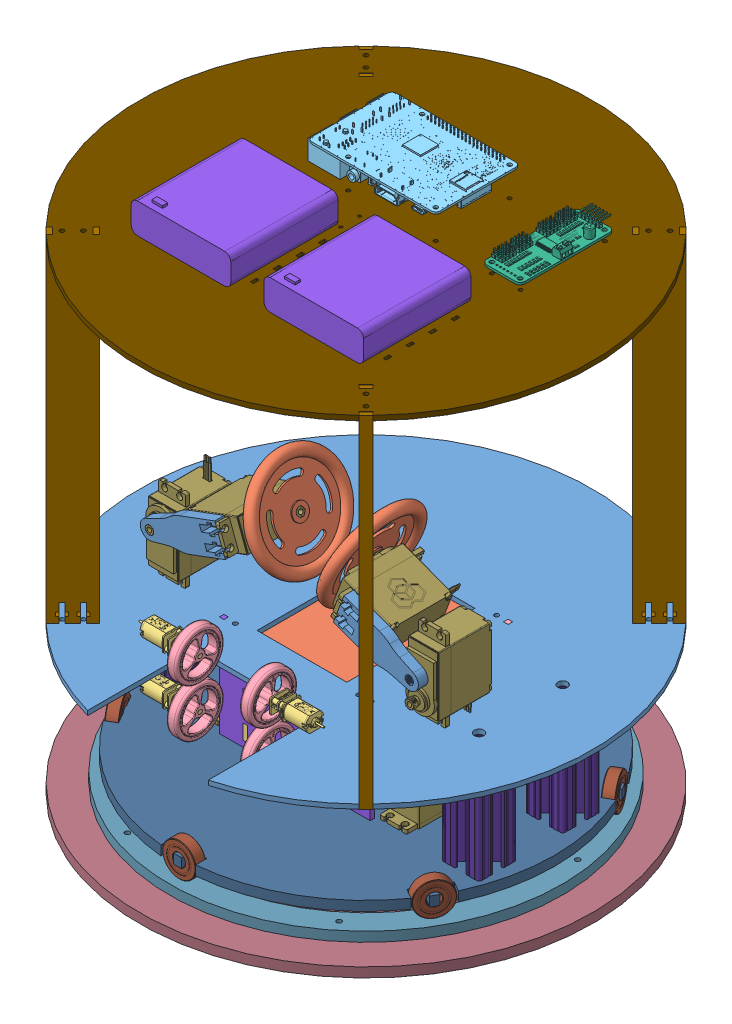
SolidWorks assembly Big_assembly, configuration Default. Lengths in mm.
Overall size (883.19 344.85 416.68).
60 component instances, 26 part files, 69 mates.
Components (placement in the parent):
- Top_Plate-1: Top_Plate [Default] at (43.1232 135.9669 213.6258) size (300 3 294.57)
- Deck-1: Deck [Default] at (43.1232 119.9669 213.6258) size (883.19 16 224.45)
- wall_long_side-1: wall_long_side [Default] at (11.6232 103.9669 213.6258) x (0 0 1) z (-1 0 0) size (94.4 64 3)
- wall_long_side-2: wall_long_side [Default] at (77.6232 103.9669 213.6258) x (0 0 1) z (-1 0 0) size (94.4 64 3)
- wall_back-1: wall_back [Default] at (43.1232 103.9669 166.4258) x (0 0 1) z (-1 0 0) size (3 67 100)
- box_bottom-1: box_bottom [Default] at (43.1232 81.8367 213.6258) size (87.5 3 88)
- Spring-1: Spring [Default] at (81.3732 96.1631 233.6258) size (7.89 47.53 7.89)
- 92125A130_TYPE 18-8 SS FLAT-HEAD SOCKET CAP SCREW-1: 92125A130_TYPE 18-8 SS FLAT-HEAD SOCKET CAP SCREW [92125A130] at (74.6232 132.4669 233.6258) x (0 -0.041478 -0.999139) z (-1 0 0) size (6 6 10.3)
- Spring-2: Spring [Default] at (4.3732 96.1631 233.6258) size (7.89 47.53 7.89)
- Spring-3: Spring [Default] at (81.3732 96.1631 193.6258) size (7.89 47.53 7.89)
- Spring-4: Spring [Default] at (4.3732 96.1631 193.6258) size (7.89 47.53 7.89)
- 92125A130_TYPE 18-8 SS FLAT-HEAD SOCKET CAP SCREW-2: 92125A130_TYPE 18-8 SS FLAT-HEAD SOCKET CAP SCREW [92125A130] at (74.6232 132.4669 193.6258) x (0 -0.041478 -0.999139) z (-1 0 0) size (6 6 10.3)
- 92125A130_TYPE 18-8 SS FLAT-HEAD SOCKET CAP SCREW-3: 92125A130_TYPE 18-8 SS FLAT-HEAD SOCKET CAP SCREW [92125A130] at (11.6232 132.4669 233.6258) x (0 0.041478 0.999139) z (1 0 0) size (6 6 10.3)
- 92125A130_TYPE 18-8 SS FLAT-HEAD SOCKET CAP SCREW-4: 92125A130_TYPE 18-8 SS FLAT-HEAD SOCKET CAP SCREW [92125A130] at (11.6232 132.4669 193.6258) x (0 0.041478 0.999139) z (1 0 0) size (6 6 10.3)
- wall_front_v02-1: wall_front_v02 [Default] at (43.1232 103.9669 260.8258) x (0 0 -1) z (1 0 0) size (3 67 100)
- 220_x_40mm_vertical_beam_1-4_in_t-slots-1: 220_x_40mm_vertical_beam_1-4_in_t-slots [Default] at (129.2665 138.9669 122.9924) x (0.707107 0 -0.707107) z (0 -1 0) size (25 6.35 226)
- assem3-1: assem3 [Default] at (169.2489 77.438 270.0894) x (0.934159 0 0.356856) z (-0.356856 0 0.934159) size (322.75 56.87 322.75)
  - lazy_susan_protoype-1: lazy_susan_protoype [Default] at (-137.9709 -17.8212 -7.7373) x (0.356856 0 0.934159) z (-0.934159 0 0.356856) size (250 6.35 250)
  - 5972K501_BALL BEARING-1: 5972K501_BALL BEARING [5972K501] at (-61.9864 -14.6462 -101.2605) x (-0.500804 -0.763962 -0.406887) z (-0.630577 0 0.776126) size (22 22 7)
  - servo-1: servo [Default] at (-83.0236 -8.9712 -18.0228) x (-0.934159 0 0.356856) z (0.356856 0 0.934159) size (20 45.1 60)
  - servo-2: servo [Default] at (-185.7811 -8.9712 21.2314) x (-0.934159 0 0.356856) z (0.356856 0 0.934159) size (20 45.1 60)
  - 5972K501_BALL BEARING-5: 5972K501_BALL BEARING [5972K501] at (-18.9852 -14.6462 11.3057) x (0.101972 -0.763962 -0.637152) z (-0.987434 0 -0.158033) size (22 22 7)
  - 5972K501_BALL BEARING-6: 5972K501_BALL BEARING [5972K501] at (-94.9697 -14.6462 104.8289) x (0.602776 -0.763962 -0.230265) z (-0.356856 0 -0.934159) size (22 22 7)
  - 5972K501_BALL BEARING-7: 5972K501_BALL BEARING [5972K501] at (-213.9555 -14.6462 85.786) x (0.500804 -0.763962 0.406887) z (0.630577 0 -0.776126) size (22 22 7)
  - base-1: base [Default] at (-137.9709 -38.3462 -7.7373) size (300 6.35 300)
  - new_rail-1: new_rail [Default] at (-137.9709 -31.9962 -7.7373) size (260 6.35 260)
  - new_base_gear-1: new_base_gear [Default] at (-137.9709 -30.0764 -7.7373) x (0 0 -1) z (0 1 0) size (59.22 59.28 6.35)
  - new_servo_gear-1: new_servo_gear [Default] at (-189.3497 -28.8212 11.8898) x (0.783336 0 0.621598) z (0 1 0) size (59.22 59.28 6.35)
  - new_servo_gear-2: new_servo_gear [Default] at (-86.5922 -27.8212 -27.3644) x (0.136575 0 0.99063) z (0 1 0) size (59.22 59.28 6.35)
  - 5972K501_BALL BEARING-8: 5972K501_BALL BEARING [5972K501] at (-256.9567 -14.6462 -26.7802) x (-0.101972 -0.763962 0.637152) z (0.987434 0 0.158033) size (22 22 7)
  - 5972K501_BALL BEARING-9: 5972K501_BALL BEARING [5972K501] at (-180.9721 -14.6462 -120.3035) x (-0.602776 -0.763962 0.230265) z (0.356856 0 0.934159) size (22 22 7)
- 47065T411_ALUMINUM T-SLOTTED FRAMING EXTRUSION-1: 47065T411_ALUMINUM T-SLOTTED FRAMING EXTRUSION [47065T411] at (-59.5768 100.9669 185.9258) x (1 0 0) z (0 -1 0) size (25.4 25.4 70)
- 47065T411_ALUMINUM T-SLOTTED FRAMING EXTRUSION-4: 47065T411_ALUMINUM T-SLOTTED FRAMING EXTRUSION [47065T411] at (-59.5768 100.9669 241.3258) x (1 0 0) z (0 1 0) size (25.4 25.4 70)
- 47065T411_ALUMINUM T-SLOTTED FRAMING EXTRUSION-5: 47065T411_ALUMINUM T-SLOTTED FRAMING EXTRUSION [47065T411] at (145.8232 100.9669 241.3258) x (-1 0 0) z (0 -1 0) size (25.4 25.4 70)
- 47065T411_ALUMINUM T-SLOTTED FRAMING EXTRUSION-6: 47065T411_ALUMINUM T-SLOTTED FRAMING EXTRUSION [47065T411] at (145.8232 100.9669 185.9258) x (-1 0 0) z (0 1 0) size (25.4 25.4 70)
- 220_x_40mm_vertical_beam_1-4_in_t-slots-2: 220_x_40mm_vertical_beam_1-4_in_t-slots [Default] at (133.7566 138.9669 299.7691) x (0.707107 0 0.707107) z (0 -1 0) size (25 6.35 226)
- 220_x_40mm_vertical_beam_1-4_in_t-slots-3: 220_x_40mm_vertical_beam_1-4_in_t-slots [Default] at (-43.0201 138.9669 304.2592) x (-0.707107 0 0.707107) z (0 -1 0) size (25 6.35 226)
- 220_x_40mm_vertical_beam_1-4_in_t-slots-4: 220_x_40mm_vertical_beam_1-4_in_t-slots [Default] at (-47.5102 138.9669 127.4825) x (-0.707107 0 -0.707107) z (0 -1 0) size (25 6.35 226)
- electronics_mount_2-1: electronics_mount_2 [Default] at (-62.9428 358.9669 319.6918) size (300 3.17 300)
- servo-1: servo [Default] at (-43.0683 165.9669 253.4758) x (1 0 0) z (0 -1 0) size (20 45.1 60)
- servo_to_servo_horn-1: servo_to_servo_horn [Default] at (-43.0683 175.9669 264.7258) x (0.937047 0.349203 0) z (0.349203 -0.937047 0) size (56 6.35 20)
- servo-2: servo [Default] at (3.7841 193.427 244.0758) x (0.349203 -0.937047 0) z (0 0 1) size (20 45.1 60)
- 2_5_8_plastic_blue_wheel_futaba_servo_hub-1: 2_5_8_plastic_blue_wheel_futaba_servo_hub [Default] at (18.7909 199.0195 234.0758) x (0.220834 -0.592585 -0.774645) z (-0.937047 -0.349203 0) size (66.67 66.67 7.62)
- micro-metal-gearmotor-backshaft-1: micro-metal-gearmotor-backshaft [Default] at (3.1232 151.9669 302.5558) x (0 0 -1) z (1 0 0) size (12 10.04 40.2)
- pololu-wheel-32x7mm-black-1: pololu-wheel-32x7mm-black [Default] at (18.8232 151.9669 302.5558) x (0 0 -1) z (1 0 0) size (32 32 8.6)
- pololu-wheel-32x7mm-black-2: pololu-wheel-32x7mm-black [Default] at (18.8232 119.9669 302.5558) x (0 0 -1) z (1 0 0) size (32 32 8.6)
- micro-metal-gearmotor-backshaft-2: micro-metal-gearmotor-backshaft [Default] at (3.1232 119.9669 302.5558) x (0 0 -1) z (1 0 0) size (12 10.04 40.2)
- pololu-wheel-32x7mm-black-3: pololu-wheel-32x7mm-black [Default] at (67.4232 151.9669 302.5558) x (0 0 1) z (-1 0 0) size (32 32 8.6)
- micro-metal-gearmotor-backshaft-3: micro-metal-gearmotor-backshaft [Default] at (83.1232 151.9669 302.5558) x (0 0 1) z (-1 0 0) size (12 10.04 40.2)
- pololu-wheel-32x7mm-black-4: pololu-wheel-32x7mm-black [Default] at (67.4232 119.9669 302.5558) x (0 0 1) z (-1 0 0) size (32 32 8.6)
- micro-metal-gearmotor-backshaft-4: micro-metal-gearmotor-backshaft [Default] at (83.1232 119.9669 302.5558) x (0 0 1) z (-1 0 0) size (12 10.04 40.2)
- 2_5_8_plastic_blue_wheel_futaba_servo_hub-2: 2_5_8_plastic_blue_wheel_futaba_servo_hub [Default] at (67.4555 199.0195 234.0758) x (-0.220834 -0.592585 -0.774645) z (-0.937047 0.349203 0) size (66.67 66.67 7.62)
- servo-3: servo [Default] at (82.4624 193.427 244.0758) x (0.349203 0.937047 0) z (0 0 1) size (20 45.1 60)
- servo_to_servo_horn-2: servo_to_servo_horn [Default] at (129.3147 175.9669 271.0758) x (-0.937047 0.349203 0) z (-0.349203 -0.937047 0) size (56 6.35 20)
- servo-4: servo [Default] at (129.3147 171.9669 253.4758) x (-1 0 0) z (0 1 0) size (20 45.1 60)
- raspberryPi3B-1: raspberryPi3B [Detailed] at (33.1232 381.4419 171.8979) x (-1 0 0) z (0 -1 0) size (87.05 58.5 19.5)
- 12Channel PWM-1: 12Channel PWM [Default] at (118.7022 367.1419 168.4479) size (25.4 7.55 66.7)
- RPi cam Rev 1.3-1: RPi cam Rev 1.3 [Výchozí] at (43.1232 352.6669 209.4758) x (-1 0 0) z (0 -1 0) size (25.2 33.1 8.7)
- battery pack-1: battery pack [Default] at (-0.8443 362.1419 256.7519) x (0 0 1) z (-1 0 0) size (71.12 21.5 66.04)
- battery pack-2: battery pack [Default] at (87.1557 362.1419 256.7519) x (0 0 1) z (-1 0 0) size (71.12 21.5 66.04)
Mates (geometry in assembly coordinates):
- Coincident1: coincident anti-aligned: plane of Top_Plate-1 through (43.1232 135.9669 213.6258) normal (0 -1 0); plane of Deck-1 through (43.1232 135.9669 213.6258) normal (0 1 0)
- Symmetric1: symmetric aligned: plane of Top_Plate-1 through (43.1232 135.9669 213.6258) normal (0 0 1); plane of Deck-1 through (11.3732 135.9669 169.1758) normal (0 0 -1); plane of Deck-1 through (11.3732 135.9669 258.0758) normal (0 0 1)
- Symmetric2: symmetric aligned: plane of Top_Plate-1 through (43.1232 135.9669 213.6258) normal (1 0 0); plane of Deck-1 through (74.8732 135.9669 258.0758) normal (1 0 0); plane of Deck-1 through (11.3732 135.9669 258.0758) normal (-1 0 0)
- Coincident2: coincident anti-aligned: plane of Top_Plate-1 through (43.1232 135.9669 213.6258) normal (0 -1 0); plane of wall_long_side-1 through (8.6232 135.9669 166.4258) normal (0 1 0)
- Parallel1: parallel anti-aligned: plane of Deck-1 through (11.3732 135.9669 258.0758) normal (-1 0 0); plane of wall_long_side-1 through (11.6232 103.9669 213.6258) normal (1 0 0)
- Symmetric3: symmetric aligned: plane of Top_Plate-1 through (43.1232 135.9669 213.6258) normal (0 0 1); plane of wall_long_side-1 through (8.6232 115.9669 169.4258) normal (0 0 -1); plane of wall_long_side-1 through (8.6232 115.9669 257.8258) normal (0 0 1)
- Coincident4: coincident anti-aligned: plane of Top_Plate-1 through (43.1232 135.9669 213.6258) normal (0 -1 0); plane of wall_back-1 through (93.1232 135.9669 169.4258) normal (0 1 0)
- Coincident5: coincident anti-aligned: plane of wall_back-1 through (43.1232 103.9669 169.4258) normal (0 0 1); plane of wall_long_side-1 through (8.6232 75.9669 169.4258) normal (0 0 -1)
- Symmetric4: symmetric aligned: plane of Top_Plate-1 through (43.1232 135.9669 213.6258) normal (1 0 0); plane of wall_back-1 through (-6.8768 71.9669 169.4258) normal (-1 0 0); plane of wall_back-1 through (93.1232 71.9669 169.4258) normal (1 0 0)
- Coincident6: coincident anti-aligned: plane of wall_long_side-2 through (74.6232 103.9669 213.6258) normal (-1 0 0); plane of wall_back-1 through (74.6232 125.8669 166.4258) normal (1 0 0)
- Parallel2: parallel anti-aligned: plane of Top_Plate-1 through (43.1232 135.9669 213.6258) normal (0 -1 0); plane of box_bottom-1 through (43.1232 84.8367 213.6258) normal (0 1 0)
- Symmetric6: symmetric aligned: plane of Top_Plate-1 through (43.1232 135.9669 213.6258) normal (0 0 1); plane of box_bottom-1 through (74.3732 84.8367 257.6258) normal (0 0 1); plane of box_bottom-1 through (74.3732 84.8367 169.6258) normal (0 0 -1)
- Symmetric7: symmetric aligned: plane of Top_Plate-1 through (43.1232 135.9669 213.6258) normal (1 0 0); plane of box_bottom-1 through (11.8732 84.8367 169.6258) normal (-1 0 0); plane of box_bottom-1 through (74.3732 84.8367 169.6258) normal (1 0 0)
- Concentric1: concentric anti-aligned: cylinder of wall_long_side-2 through (71.6232 132.4669 233.6258) axis (1 0 0) radius 1.4224; cylinder of 92125A130_TYPE 18-8 SS FLAT-HEAD SOCKET CAP SCREW-1 through (74.6232 132.4669 233.6258) axis (-1 0 0) radius 3
- Coincident10: coincident aligned: plane of wall_long_side-2 through (74.6232 103.9669 213.6258) normal (-1 0 0); plane of 92125A130_TYPE 18-8 SS FLAT-HEAD SOCKET CAP SCREW-1 through (74.6232 133.9656 233.5636) normal (-1 0 0)
- Concentric4: concentric aligned: circle of Spring-1; circle of 92125A130_TYPE 18-8 SS FLAT-HEAD SOCKET CAP SCREW-1
- Parallel4: parallel aligned: plane of wall_long_side-2 through (77.6232 103.9669 213.6258) normal (1 0 0); plane of Spring-1 through (81.3732 96.1631 233.6258) normal (1 0 0)
- Distance1: distance = 3.75 mm aligned: plane of Spring-1 through (81.3732 96.1631 233.6258) normal (1 0 0); plane of wall_long_side-2 through (77.6232 103.9669 213.6258) normal (1 0 0)
- Coincident14: coincident anti-aligned: plane of Top_Plate-1 through (43.1232 135.9669 213.6258) normal (0 -1 0); plane of wall_front_v02-1 through (-6.8768 135.9669 257.8258) normal (0 1 0)
- Parallel5: parallel anti-aligned: plane of Deck-1 through (11.3732 135.9669 258.0758) normal (0 0 1); plane of wall_front_v02-1 through (43.1232 103.9669 257.8258) normal (0 0 -1)
- Symmetric8: symmetric aligned: plane of Top_Plate-1 through (43.1232 135.9669 213.6258) normal (1 0 0); plane of wall_front_v02-1 through (93.1232 71.9669 257.8258) normal (1 0 0); plane of wall_front_v02-1 through (-6.8768 71.9669 257.8258) normal (-1 0 0)
- Coincident16: coincident anti-aligned: plane of wall_long_side-1 through (8.6232 75.9669 257.8258) normal (0 0 1); plane of wall_front_v02-1 through (43.1232 103.9669 257.8258) normal (0 0 -1)
- Coincident17: coincident anti-aligned: plane of Top_Plate-1 through (43.1232 138.9669 213.6258) normal (0 1 0); plane of 220_x_40mm_vertical_beam_1-4_in_t-slots-1 through (140.0657 138.9669 121.1734) normal (0 -1 0)
- Concentric5: concentric aligned: cylinder of Top_Plate-1 through (43.1232 138.9669 213.6258) axis (0 -1 0) radius 150; cylinder of assem3-1/lazy_susan_protoype-1 through (43.1232 65.9669 213.6258) axis (0 -1 0) radius 125
- Parallel6: parallel aligned: plane of wall_long_side-1 through (8.6232 103.9669 213.6258) normal (-1 0 0); plane of assem3-1/servo-2 through (-21.8768 88.4669 243.1258) normal (-1 0 0)
- Coincident20: coincident anti-aligned: plane of assem3-1/lazy_susan_protoype-1 through (43.1232 65.9669 213.6258) normal (0 1 0); plane of 47065T411_ALUMINUM T-SLOTTED FRAMING EXTRUSION-1 through (-65.9932 65.9669 176.516) normal (0 -1 0)
- Parallel7: parallel aligned: plane of wall_long_side-1 through (8.6232 103.9669 213.6258) normal (-1 0 0); plane of 47065T411_ALUMINUM T-SLOTTED FRAMING EXTRUSION-1 through (-72.2768 65.9669 195.4762) normal (-1 0 0)
- Distance4: distance = 25 mm anti-aligned: plane of 47065T411_ALUMINUM T-SLOTTED FRAMING EXTRUSION-1 through (-46.8768 65.9669 176.3754) normal (1 0 0); plane of assem3-1/servo-2 through (-21.8768 88.4669 243.1258) normal (-1 0 0)
- Coincident27: coincident anti-aligned: plane of Top_Plate-1 through (43.1232 135.9669 213.6258) normal (0 -1 0); plane of 47065T411_ALUMINUM T-SLOTTED FRAMING EXTRUSION-1 through (-65.9932 135.9669 176.516) normal (0 1 0)
- Distance6: distance = 15 mm aligned: plane of Top_Plate-1 through (43.1232 135.9669 213.6258) normal (0 0 1); plane of 47065T411_ALUMINUM T-SLOTTED FRAMING EXTRUSION-1 through (-65.9099 65.9669 198.6258) normal (0 0 1)
- Symmetric10: symmetric aligned: plane of Top_Plate-1 through (43.1232 135.9669 213.6258) normal (0.707107 0 0.707107); plane of 220_x_40mm_vertical_beam_1-4_in_t-slots-1 through (133.7566 138.9669 127.4825) normal (0.707107 0 0.707107); plane of 220_x_40mm_vertical_beam_1-4_in_t-slots-1 through (129.2665 138.9669 122.9924) normal (-0.707107 0 -0.707107)
- Tangent6: tangent aligned: cylinder of Top_Plate-1 through (43.1232 138.9669 213.6258) axis (0 -1 0) radius 150; plane of 220_x_40mm_vertical_beam_1-4_in_t-slots-1 through (151.4343 358.9669 109.8048) normal (0.707107 0 -0.707107)
- Coincident28: coincident anti-aligned: plane of 220_x_40mm_vertical_beam_1-4_in_t-slots-4 through (-49.3292 358.9669 116.6833) normal (0 1 0); plane of electronics_mount_2-1 through (-62.9428 358.9669 319.6918) normal (0 -1 0)
- Concentric6: concentric aligned: cylinder of Top_Plate-1 through (43.1232 138.9669 213.6258) axis (0 -1 0) radius 150; cylinder of electronics_mount_2-1 through (43.1232 362.1419 213.6258) axis (0 -1 0) radius 150
- Parallel9: parallel aligned: plane of Deck-1 through (11.3732 135.9669 258.0758) normal (-1 0 0); plane of electronics_mount_2-1 through (36.1557 362.1419 319.6918) normal (-1 0 0)
- Parallel10: parallel aligned: plane of Top_Plate-1 through (43.1232 138.9669 213.6258) normal (0 1 0); plane of servo-1 through (-33.5683 185.9669 233.4758) normal (0 1 0)
- Parallel11: parallel aligned: plane of Top_Plate-1 through (3.1232 135.9669 286.5558) normal (0 0 1); plane of servo-1 through (-43.0683 175.9669 263.9758) normal (0 0 1)
- Coincident31: coincident anti-aligned: plane of Top_Plate-1 through (43.1232 138.9669 213.6258) normal (0 1 0); plane of servo-1 through (-47.0683 138.9669 255.9758) normal (0 -1 0)
- Distance9: distance = 15 mm anti-aligned: plane of servo-1 through (-43.0683 175.9669 271.0758) normal (0 0 1); plane of Top_Plate-1 through (13.3732 138.9669 256.0758) normal (0 0 -1)
- Parallel13: parallel aligned: plane of 47065T411_ALUMINUM T-SLOTTED FRAMING EXTRUSION-4 through (-55.0683 135.9669 242.919) normal (1 0 0); plane of servo-1 through (-33.0683 146.4669 255.9758) normal (1 0 0)
- Coincident34: coincident aligned: plane of servo-1 through (-43.0683 175.9669 271.0758) normal (0 0 1); plane of servo_to_servo_horn-1 through (-15.3421 173.1583 271.0758) normal (0 0 1)
- Concentric7: concentric aligned: circle of servo-1; circle of servo_to_servo_horn-1
- Parallel12: parallel aligned: plane of servo_to_servo_horn-1 through (4.8142 190.6627 271.0758) normal (0.937047 0.349203 0); plane of servo-2 through (15.9657 197.9666 234.0758) normal (0.937047 0.349203 0)
- Coincident36: coincident aligned: plane of servo_to_servo_horn-1 through (-15.3421 173.1583 271.0758) normal (0 0 1); plane of servo-2 through (4.7299 198.0482 271.0758) normal (0 0 1)
- Symmetric11: symmetric anti-aligned: plane of servo_to_servo_horn-1 through (-43.0683 175.9669 264.7258) normal (0.349203 -0.937047 0); line of servo-2 through (2.9839 202.7334 264.0758) axis (0 0 1); line of servo-2 through (9.2695 185.8666 270.0758) axis (0 0 -1)
- Concentric8: concentric anti-aligned: circle of servo-2; circle of 2_5_8_plastic_blue_wheel_futaba_servo_hub-1
- Coincident37: coincident aligned: plane of servo-2 through (20.2761 199.573 234.0758) normal (0.937047 0.349203 0); plane of 2_5_8_plastic_blue_wheel_futaba_servo_hub-1 through (20.2761 199.573 234.0758) normal (0.937047 0.349203 0)
- Coincident38: coincident anti-aligned: plane of servo_to_servo_horn-1 through (1.3222 200.0332 271.0758) normal (0.937047 0.349203 0); plane of servo-2 through (0.4666 202.329 224.5758) normal (-0.937047 -0.349203 0)
- Distance8: distance = 2 mm anti-aligned: plane of servo-1 through (-53.0683 185.4669 233.4758) normal (-1 0 0); plane of 47065T411_ALUMINUM T-SLOTTED FRAMING EXTRUSION-4 through (-55.0683 135.9669 242.919) normal (1 0 0)
- Concentric9: concentric anti-aligned: circle of micro-metal-gearmotor-backshaft-1; circle of pololu-wheel-32x7mm-black-1
- Coincident41: coincident aligned: plane of micro-metal-gearmotor-backshaft-1 through (22.1232 151.9669 302.5558) normal (1 0 0); plane of pololu-wheel-32x7mm-black-1 through (22.1232 151.9669 302.5558) normal (1 0 0)
- Parallel16: parallel anti-aligned: plane of Top_Plate-1 through (43.1232 138.9669 213.6258) normal (0 1 0); plane of micro-metal-gearmotor-backshaft-1 through (-10.8768 146.9669 302.5558) normal (0 -1 0)
- Coincident44: coincident anti-aligned: plane of Top_Plate-1 through (3.1232 135.9669 286.5558) normal (1 0 0); plane of micro-metal-gearmotor-backshaft-1 through (3.1232 146.9669 308.5558) normal (-1 0 0)
- Distance10: distance = 8 mm anti-aligned: plane of micro-metal-gearmotor-backshaft-1 through (-10.8768 146.9669 302.5558) normal (0 -1 0); plane of Top_Plate-1 through (43.1232 138.9669 213.6258) normal (0 1 0)
- Coincident46: coincident anti-aligned: plane of micro-metal-gearmotor-backshaft-1 through (22.1232 152.9669 303.6738) normal (0 1 0); plane of pololu-wheel-32x7mm-black-1 through (13.5232 152.9669 301.4378) normal (0 -1 0)
- Tangent7: tangent anti-aligned: plane of Top_Plate-1 through (3.1232 135.9669 286.5558) normal (0 0 1); cylinder of pololu-wheel-32x7mm-black-1 through (22.1232 151.9669 302.5558) axis (1 0 0) radius 16
- Parallel17: parallel anti-aligned: plane of electronics_mount_2-1 through (-62.9428 362.1419 319.6918) normal (0 1 0); plane of raspberryPi3B-1 through (33.1232 380.1419 171.8979) normal (0 -1 0)
- Concentric10: concentric aligned: cylinder of electronics_mount_2-1 through (72.1232 362.1419 147.3979) axis (0 -1 0) radius 1.25; cylinder of raspberryPi3B-1 through (72.1232 381.4419 147.3979) axis (0 -1 0) radius 1.375
- Distance11: distance = 18 mm anti-aligned: plane of raspberryPi3B-1 through (33.1232 380.1419 171.8979) normal (0 -1 0); plane of electronics_mount_2-1 through (-62.9428 362.1419 319.6918) normal (0 1 0)
- Parallel18: parallel aligned: plane of Top_Plate-1 through (13.3732 138.9669 171.1758) normal (0 0 1); plane of raspberryPi3B-1 through (75.6232 380.1419 199.8979) normal (0 0 1)
- Concentric11: concentric anti-aligned: cylinder of electronics_mount_2-1 through (109.3022 362.1419 196.3979) axis (0 -1 0) radius 1.25; cylinder of 12Channel PWM-1 through (109.3022 363.6063 196.3979) axis (0 1 0) radius 1.25
- Parallel19: parallel anti-aligned: plane of raspberryPi3B-1 through (75.6232 380.1419 143.8979) normal (1 0 0); plane of 12Channel PWM-1 through (106.0022 368.6419 140.4979) normal (-1 0 0)
- Distance12: distance = 5 mm anti-aligned: plane of 12Channel PWM-1 through (128.1022 367.1419 140.4979) normal (0 -1 0); plane of electronics_mount_2-1 through (-62.9428 362.1419 319.6918) normal (0 1 0)
- Concentric12: concentric aligned: cylinder of electronics_mount_2-1 through (32.6232 362.1419 207.3758) axis (0 -1 0) radius 1; cylinder of RPi cam Rev 1.3-1 through (32.6232 353.6669 207.3758) axis (0 -1 0) radius 1.05
- Distance13: distance = 4 mm anti-aligned: plane of RPi cam Rev 1.3-1 through (43.1232 354.9669 209.4758) normal (0 1 0); plane of electronics_mount_2-1 through (-62.9428 358.9669 319.6918) normal (0 -1 0)
- Parallel20: parallel aligned: plane of raspberryPi3B-1 through (9.9232 366.8419 197.6479) normal (0 0 1); plane of RPi cam Rev 1.3-1 through (43.1232 353.6669 221.4758) normal (0 0 1)
- Symmetric12: symmetric aligned: plane of electronics_mount_2-1 through (-35.8443 362.1419 319.6918) normal (-1 0 0); plane of electronics_mount_2-1 through (34.1557 362.1419 319.6918) normal (1 0 0); plane of battery pack-1 through (-0.8443 362.1419 256.7519) normal (-1 0 0)
- Symmetric13: symmetric aligned: plane of electronics_mount_2-1 through (-62.9428 362.1419 277.2519) normal (0 0 1); plane of electronics_mount_2-1 through (-62.9428 362.1419 236.2519) normal (0 0 -1); plane of battery pack-1 through (-0.8443 362.1419 256.7519) normal (0 0 1)
- Coincident54: coincident anti-aligned: plane of electronics_mount_2-1 through (-62.9428 362.1419 319.6918) normal (0 1 0); plane of battery pack-1 through (-0.8443 362.1419 256.7519) normal (0 -1 0)
